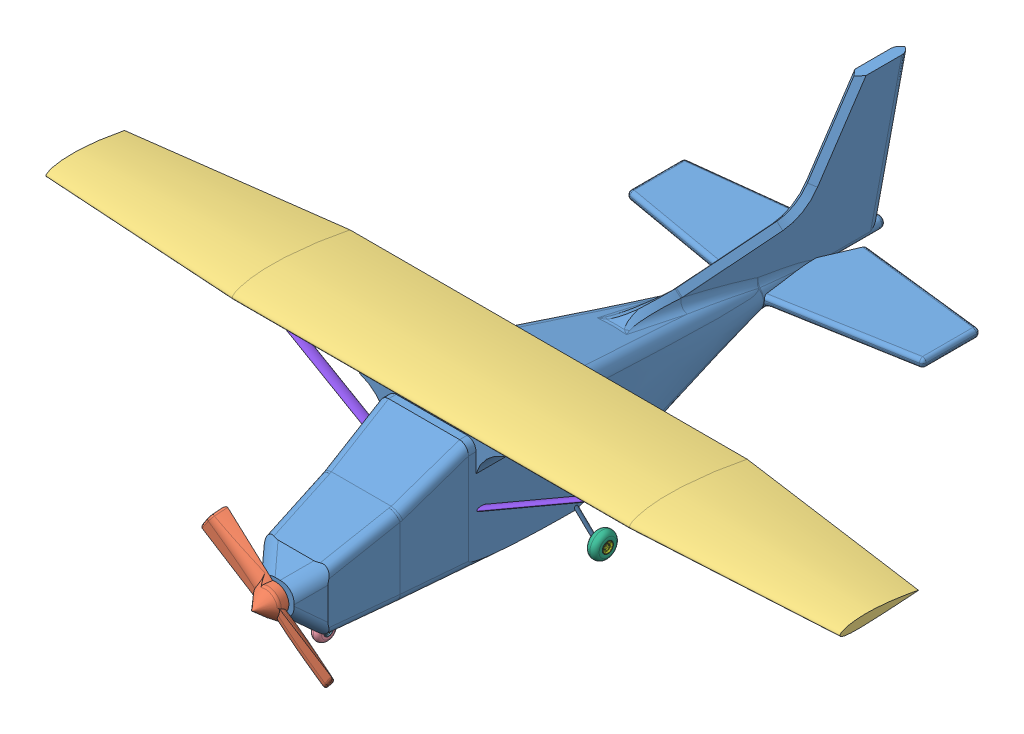
SolidWorks assembly FullAssembly, configuration Default. Lengths in mm.
Overall size (10981.26 3151.47 9019.51).
17 component instances, 10 part files, 20 mates.
Components (placement in the parent):
- BodyPropper-1: BodyPropper [Default] at (3093.3173 3170.968 11174.4928) size (4083.77 2691.03 8663.91)
- PropPropper-1: PropPropper [Default] at (3093.3173 3170.968 11453.8928) x (0.740961 -0.671548 0) z (0 0 1) size (2048.16 562.64 457.2)
- cessnaWing-1: cessnaWing [Default] at (350.1173 4304.8621 9311.4865) x (0 0 -1) z (1 0 0) size (1757.58 310.78 10981.26)
- 5.00-5 wheel and tire assembly-2: 5.00-5 wheel and tire assembly [Default] at (3027.9005 2621.2237 10415.7509) x (1 0 0) z (0 -0.756315 0.654208) size (130.34 292.13 292.13)
  - Tire 5.00-5-1: Tire 5.00-5 [Default] at (67.5419 180.3345 364.7938) size (130.34 292.13 292.13)
  - Wheel 5.00-5-1: Wheel 5.00-5 [Default] at (48.0472 180.3345 364.7938) size (127 127 127)
- 6.00-6 wheel and tire assembly-2: 6.00-6 wheel and tire assembly [Default] at (2570.3992 2397.2144 7788.3244) size (159.37 343.14 343.14)
  - tire 6.00-6-1: tire 6.00-6 [Default] at (-445.3299 120.4843 141.4975) size (159.37 343.14 343.14)
  - Wheel 6.00-6-1: Wheel 6.00-6 [Default] at (-470.7299 120.4843 141.4975) size (152.4 165.1 165.1)
- WingStrut-1: WingStrut [Default] at (2493.3502 3418.7761 9197.9828) x (0 0 1) z (-0.866025 0.5 0) size (135.56 53.25 1778)
- WingStrut-2: WingStrut [Default] at (3693.2843 3418.7761 9222.5793) x (0 0 -1) z (0.866025 0.5 0) size (135.56 53.25 1778)
- Front Gear-1: Front Gear [Default] at (3101.3477 2575.1816 10696.9123) x (-1 0 0) z (0 -0.642788 -0.766044) size (155.1 412.75 53.5)
- 6.00-6 wheel and tire assembly-3: 6.00-6 wheel and tire assembly [Default] at (3616.2353 2584.3314 8083.1032) x (-1 0 0) z (0 -0.889175 -0.457567) size (159.37 343.14 343.14)
  - tire 6.00-6-1: tire 6.00-6 [Default] at (-445.3299 120.4843 141.4975) size (159.37 343.14 343.14)
  - Wheel 6.00-6-1: Wheel 6.00-6 [Default] at (-470.7299 120.4843 141.4975) size (152.4 165.1 165.1)
- LandingGearBack-1: LandingGearBack [Default] at (2480.6693 2784.3987 7925.0802) x (0 0 1) z (-1 0 0) size (56.13 304.81 330.21)
- LandingGearBack-2: LandingGearBack [Default] at (3705.9653 2780.3449 7915.9687) x (0 0 -1) z (1 0 0) size (56.13 304.81 330.21)
Mates (geometry in assembly coordinates):
- Concentric1: concentric aligned: cylinder of BodyPropper-1 through (3093.3173 3170.968 11174.4928) axis (0 0 1) radius 12.7; cylinder of PropPropper-1 through (3093.3173 3170.968 11326.8928) axis (0 0 1) radius 25.4
- Distance2: distance = 25.4 mm anti-aligned: plane of PropPropper-1 through (3093.3173 3170.968 11453.8928) normal (0 0 -1); plane of BodyPropper-1 through (3093.3173 3170.968 11428.4928) normal (0 0 1)
- Coincident3: coincident anti-aligned: plane of BodyPropper-1 through (3093.3173 4285.8121 11174.4928) normal (0 1 0); plane of cessnaWing-1 through (350.1173 4285.8121 9311.4865) normal (0 -1 0)
- Tangent1: tangent: plane of BodyPropper-1 through (2093.3193 4285.8121 7685.8028) normal (-1 0 0); curve of cessnaWing-1
- Coincident5: coincident aligned: line of BodyPropper-1 through (4093.3153 4285.8121 9300.7348) axis (-1 0 0); line of cessnaWing-1 through (4093.3153 4285.8121 9300.7348) axis (-1 0 0)
- Coincident17: coincident: plane of BodyPropper-1 through (3093.3173 4285.8121 11174.4928) normal (0 1 0); plane of WingStrut-1 through (940.8761 4285.8121 9130.2029) normal (0 1 0)
- Distance4: distance = 0 mm anti-aligned: plane of WingStrut-1 through (2480.6693 3396.8121 9130.2029) normal (1 0 0); plane of BodyPropper-1 through (2480.6693 3170.968 11174.4928) normal (-1 0 0)
- Coincident19: coincident: plane of BodyPropper-1 through (3093.3173 4285.8121 11174.4928) normal (0 1 0); plane of WingStrut-2 through (5245.7584 4285.8121 9290.3592) normal (0 1 0)
- Coincident20: coincident anti-aligned: plane of BodyPropper-1 through (3705.9653 3170.968 11174.4928) normal (1 0 0); plane of WingStrut-2 through (3705.9653 3396.8121 9290.3592) normal (-1 0 0)
- Coincident21: coincident anti-aligned: plane of BodyPropper-1 through (3093.3173 2753.4301 11174.4928) normal (0 -1 0); plane of Front Gear-1 through (3177.5477 2753.4301 10514.1867) normal (0 1 0)
- Parallel10: parallel anti-aligned: line of BodyPropper-1 through (2845.4246 2753.4301 11174.4928) axis (1 0 0); cylinder of Front Gear-1 through (3177.5477 2463.3008 10790.7914) axis (-1 0 0) radius 12.7
- Parallel12: parallel: line of BodyPropper-1 through (2845.4246 2753.4301 11174.4928) axis (1 0 0); plane of Front Gear-1 through (3049.1975 2463.3008 10790.7914) normal (0 -0.766044 0.642788)
- Concentric2: concentric aligned: cylinder of 5.00-5 wheel and tire assembly-2/Wheel 5.00-5-1 through (3075.9477 2463.3008 10790.7914) axis (-1 0 0) radius 12.7; cylinder of Front Gear-1 through (3177.5477 2463.3008 10790.7914) axis (-1 0 0) radius 12.7
- Tangent3: tangent anti-aligned: plane of 5.00-5 wheel and tire assembly-2/Wheel 5.00-5-1 through (3075.9477 2471.6092 10800.3966) normal (-1 0 0); cylinder of Front Gear-1 through (3049.1975 2463.3008 10790.7914) axis (0 0.766044 -0.642788) radius 26.7502
- Coincident26: coincident anti-aligned: plane of BodyPropper-1 through (2480.6693 3170.968 11174.4928) normal (-1 0 0); plane of LandingGearBack-1 through (2480.6693 2784.3987 7925.0802) normal (1 0 0)
- Concentric3: concentric anti-aligned: cylinder of 6.00-6 wheel and tire assembly-2/Wheel 6.00-6-1 through (2099.6693 2517.6987 7929.8219) axis (-1 0 0) radius 12.7; cylinder of LandingGearBack-1 through (2150.4693 2517.6987 7929.8219) axis (1 0 0) radius 12.7
- Tangent6: tangent: plane of 6.00-6 wheel and tire assembly-2/Wheel 6.00-6-1 through (2201.2693 2530.3987 7929.8219) normal (1 0 0); circle of LandingGearBack-1
- Coincident29: coincident anti-aligned: plane of BodyPropper-1 through (3705.9653 3170.968 11174.4928) normal (1 0 0); plane of LandingGearBack-2 through (3705.9653 2780.3449 7915.9687) normal (-1 0 0)
- Tangent8: tangent: plane of 6.00-6 wheel and tire assembly-3/Wheel 6.00-6-1 through (3985.3653 2519.456 7899.9344) normal (-1 0 0); circle of LandingGearBack-2
- Concentric5: concentric anti-aligned: cylinder of 6.00-6 wheel and tire assembly-3/Wheel 6.00-6-1 through (4086.9653 2513.6449 7911.227) axis (1 0 0) radius 12.7; cylinder of LandingGearBack-2 through (4036.1653 2513.6449 7911.227) axis (-1 0 0) radius 12.7
